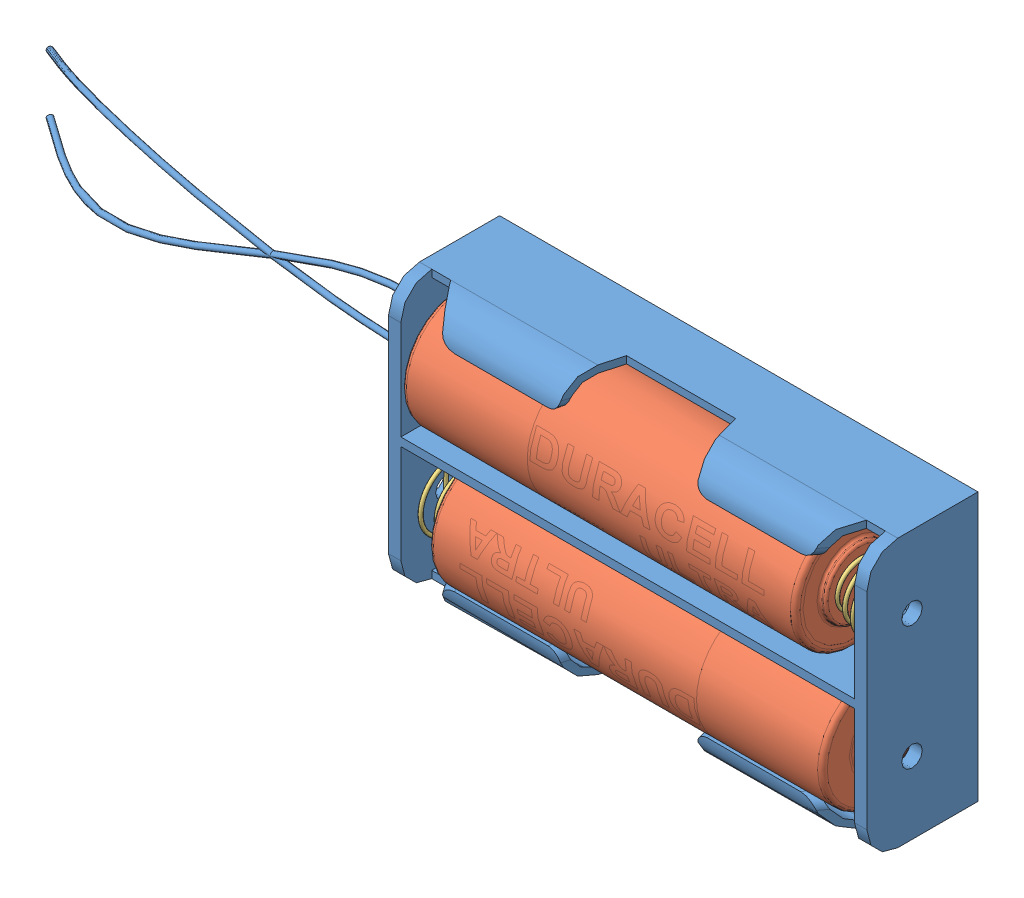
SolidWorks assembly AA holder 3Dcontentcentral, configuration Default. Lengths in mm.
Overall size (117.46 33.02 18.65).
5 component instances, 3 part files, 10 mates.
Components (placement in the parent):
- User Library-2ea.aa.in_holder_R6.AA.UM3-1.5V.holder-2: User Library-2ea.aa.in_holder_R6.AA.UM3-1.5V.holder [Default] at origin size (117.46 33.02 16.96)
- User Library-2ea.aa.in_holder_SW3dPS-duracell ultra aa 1_5v mx 1500 lr6-2: User Library-2ea.aa.in_holder_SW3dPS-duracell ultra aa 1_5v mx 1500 lr6 [Default] at (22.072 7.62 8.128) x (0 1 0) z (0 0 1) size (14.5 50.25 14.5)
- User Library-2ea.aa.in_holder_SW3dPS-Conical Spring-1: User Library-2ea.aa.in_holder_SW3dPS-Conical Spring [Default] at (27.94 7.62 8.128) x (0 0 1) z (-1 0 0) size (9.14 9.07 7.74)
- User Library-2ea.aa.in_holder_SW3dPS-Conical Spring-2: User Library-2ea.aa.in_holder_SW3dPS-Conical Spring [Default] at (-27.94 -7.62 8.128) x (0 0 -1) z (1 0 0) size (9.14 9.07 7.74)
- User Library-2ea.aa.in_holder_SW3dPS-duracell ultra aa 1_5v mx 1500 lr6-3: User Library-2ea.aa.in_holder_SW3dPS-duracell ultra aa 1_5v mx 1500 lr6 [Default] at (-22.58 -7.62 8.128) x (0 -1 0) z (0 0 1) size (14.5 50.25 14.5)
Mates (geometry in assembly coordinates):
- Concentric1: concentric anti-aligned: circle of User Library-2ea.aa.in_holder_R6.AA.UM3-1.5V.holder-2; circle of User Library-2ea.aa.in_holder_SW3dPS-duracell ultra aa 1_5v mx 1500 lr6-2
- Distance1: distance = 0.762 mm anti-aligned: plane of User Library-2ea.aa.in_holder_R6.AA.UM3-1.5V.holder-2 through (-27.94 12.7 9.8806) normal (1 0 0); plane of User Library-2ea.aa.in_holder_SW3dPS-duracell ultra aa 1_5v mx 1500 lr6-2 through (-27.178 7.62 8.128) normal (-1 0 0)
- Coincident3: coincident aligned: plane of User Library-2ea.aa.in_holder_R6.AA.UM3-1.5V.holder-2 through (27.94 12.7 9.8806) normal (-1 0 0); plane of User Library-2ea.aa.in_holder_SW3dPS-Conical Spring-1 through (27.94 7.62 8.128) normal (-1 0 0)
- Coincident4: coincident: axis of User Library-2ea.aa.in_holder_R6.AA.UM3-1.5V.holder-2 through (27.94 7.62 8.128) axis (1 0 0); plane of User Library-2ea.aa.in_holder_SW3dPS-Conical Spring-1 through (27.94 7.62 8.128) normal (0 0 1)
- Coincident5: coincident: axis of User Library-2ea.aa.in_holder_R6.AA.UM3-1.5V.holder-2 through (27.94 7.62 8.128) axis (1 0 0); plane of User Library-2ea.aa.in_holder_SW3dPS-Conical Spring-1
- Coincident6: coincident aligned: plane of User Library-2ea.aa.in_holder_R6.AA.UM3-1.5V.holder-2 through (-27.94 -12.7 9.8806) normal (1 0 0); plane of User Library-2ea.aa.in_holder_SW3dPS-Conical Spring-2 through (-27.94 -7.62 8.128) normal (1 0 0)
- Coincident7: coincident: axis of User Library-2ea.aa.in_holder_R6.AA.UM3-1.5V.holder-2 through (-29.464 -7.62 8.128) axis (1 0 0); plane of User Library-2ea.aa.in_holder_SW3dPS-Conical Spring-2
- Coincident8: coincident: axis of User Library-2ea.aa.in_holder_R6.AA.UM3-1.5V.holder-2 through (-29.464 -7.62 8.128) axis (1 0 0); plane of User Library-2ea.aa.in_holder_SW3dPS-Conical Spring-2 through (-27.94 -7.62 8.128) normal (0 0 -1)
- Distance2: distance = 1.27 mm anti-aligned: plane of User Library-2ea.aa.in_holder_R6.AA.UM3-1.5V.holder-2 through (27.94 -12.7 9.8806) normal (-1 0 0); plane of User Library-2ea.aa.in_holder_SW3dPS-duracell ultra aa 1_5v mx 1500 lr6-3 through (26.67 -7.62 8.128) normal (1 0 0)
- Concentric2: concentric aligned: circle of User Library-2ea.aa.in_holder_R6.AA.UM3-1.5V.holder-2; circle of User Library-2ea.aa.in_holder_SW3dPS-duracell ultra aa 1_5v mx 1500 lr6-3
